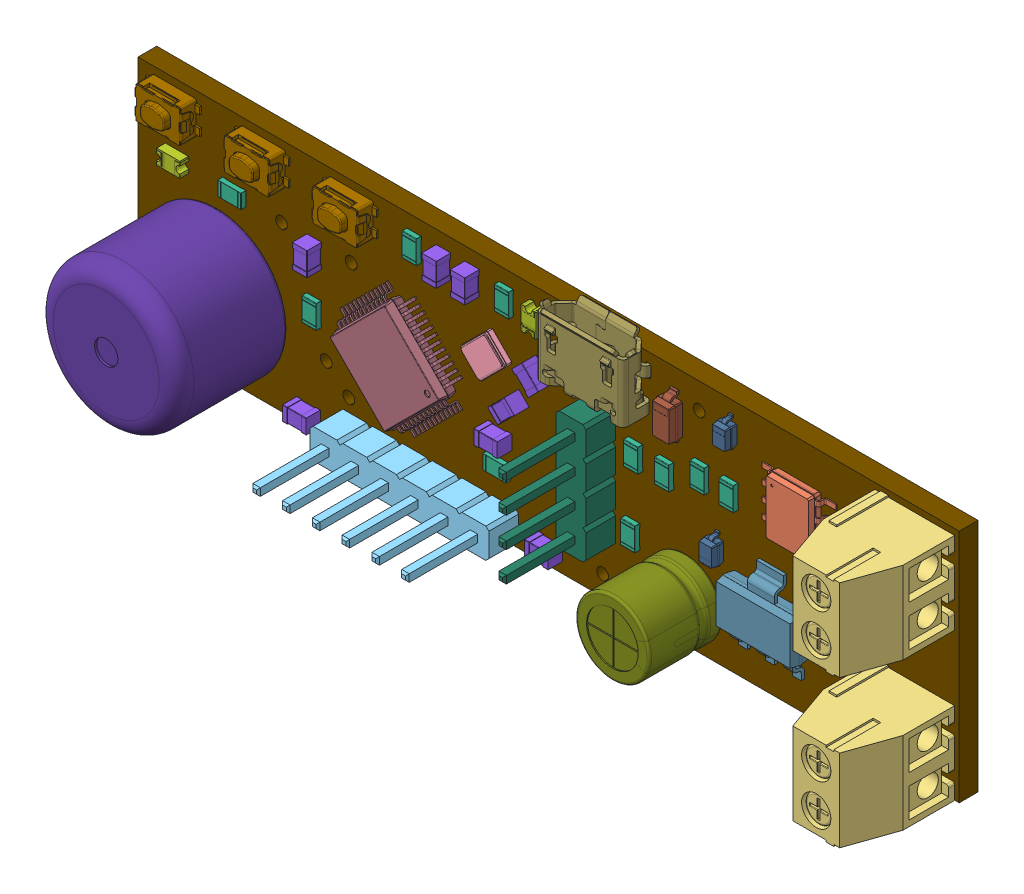
SolidWorks assembly SPD_DC_MotorHBridge, configuration Default. Lengths in mm.
Overall size (70.04 21.75 12.53).
84 component instances, 18 part files, 0 mates.
Components (placement in the parent):
- SPD_DC_MotorHBridge.step-1: SPD_DC_MotorHBridge.step [Default] at origin size (70.04 21.75 12.53)
  - R_1206_3216Metric.step-1: R_1206_3216Metric.step [Default] at (61.7855 -6.223 1.65) x (0 -1 0) z (0 0 1) size (3.2 1.6 0.55)
    - SOLID.step-1: SOLID.step [Default] at origin size (3.2 1.6 0.55)
  - HSOP-8-1EP_3.9x4.9mm_P1.27mm_EP2.41x3.1mm.step-1: HSOP-8-1EP_3.9x4.9mm_P1.27mm_EP2.41x3.1mm.step [Default] at (56.515 -5.2705 1.65) size (6.3 4.9 1.1)
    - SOLID-0.step-1: SOLID-0.step [Default] at origin size (6.3 4.9 1.1)
  - Screw_Terminal_Block_3.5mm_Blue_2-way.step-1: Screw_Terminal_Block_3.5mm_Blue_2-way.step [Default] at (66.294 -3.965 1.65) x (0 1 0) z (1 0 0) size (7.3 10.4 6.8)
    - COMPOUND.step-1: COMPOUND.step [Default] at origin size (7.3 10.4 6.8)
  - Crystal_SMD_SeikoEpson_TSX3225-4Pin_3.2x2.5mm_HandSoldering.step-1: Crystal_SMD_SeikoEpson_TSX3225-4Pin_3.2x2.5mm_HandSoldering.step [Default] at (29.972 -6.858 1.65) x (0.707107 0.707107 0) z (0 0 1) size (3.2 2.5 0.64)
    - SOLID-1.step-1: SOLID-1.step [Default] at origin size (3.2 2.5 0.64)
  - PinHeader_1x06_P2.54mm_Vertical.step-1: PinHeader_1x06_P2.54mm_Vertical.step [Default] at (31.242 -18.4912 1.65) x (0 -1 0) z (0 0 1) size (2.54 15.24 11.54)
    - SOLID-2.step-1: SOLID-2.step [Default] at origin size (2.54 15.24 11.54)
  - R_0805_2012Metric.step-1: R_0805_2012Metric.step [Default] at (31.496 -2.0828 1.65) x (0 1 0) z (0 0 1) size (2 1.2 0.45)
    - SOLID-3.step-1: SOLID-3.step [Default] at origin size (2 1.2 0.45)
  - D_0805_2012Metric.step-1: D_0805_2012Metric.step [Default] at (34.1376 -2.0828 1.65) x (0 1 0) z (0 0 1) size (2 1.27 0.8)
    - SOLID-4.step-1: SOLID-4.step [Default] at origin size (2 1.27 0.8)
  - R_0805_2012Metric.step-2: R_0805_2012Metric.step [Default] at (8.2804 -5.7912 1.65) x (-1 0 0) z (0 0 1) size (2 1.2 0.45)
    - SOLID-3.step-1: SOLID-3.step [Default] at origin size (2 1.2 0.45)
  - D_0805_2012Metric.step-2: D_0805_2012Metric.step [Default] at (3.4036 -5.7404 1.65) size (2 1.27 0.8)
    - SOLID-4.step-1: SOLID-4.step [Default] at origin size (2 1.27 0.8)
  - R_0805_2012Metric.step-3: R_0805_2012Metric.step [Default] at (23.622 -2.0828 1.65) x (0 -1 0) z (0 0 1) size (2 1.2 0.45)
    - SOLID-3.step-1: SOLID-3.step [Default] at origin size (2 1.2 0.45)
  - R_0805_2012Metric.step-4: R_0805_2012Metric.step [Default] at (42.5196 -8.0264 1.65) x (0 1 0) z (0 0 1) size (2 1.2 0.45)
    - SOLID-3.step-1: SOLID-3.step [Default] at origin size (2 1.2 0.45)
  - R_0805_2012Metric.step-5: R_0805_2012Metric.step [Default] at (45.1612 -8.0264 1.65) x (0 1 0) z (0 0 1) size (2 1.2 0.45)
    - SOLID-3.step-1: SOLID-3.step [Default] at origin size (2 1.2 0.45)
  - R_0805_2012Metric.step-6: R_0805_2012Metric.step [Default] at (42.2656 -13.97 1.65) x (0 1 0) z (0 0 1) size (2 1.2 0.45)
    - SOLID-3.step-1: SOLID-3.step [Default] at origin size (2 1.2 0.45)
  - R_0805_2012Metric.step-7: R_0805_2012Metric.step [Default] at (36.83 -13.97 1.65) x (0 1 0) z (0 0 1) size (2 1.2 0.45)
    - SOLID-3.step-1: SOLID-3.step [Default] at origin size (2 1.2 0.45)
  - R_0805_2012Metric.step-8: R_0805_2012Metric.step [Default] at (30.8864 -14.6812 1.65) size (2 1.2 0.45)
    - SOLID-3.step-1: SOLID-3.step [Default] at origin size (2 1.2 0.45)
  - R_0805_2012Metric.step-9: R_0805_2012Metric.step [Default] at (15.0876 -11.1252 1.65) x (0 -1 0) z (0 0 1) size (2 1.2 0.45)
    - SOLID-3.step-1: SOLID-3.step [Default] at origin size (2 1.2 0.45)
  - R_0805_2012Metric.step-10: R_0805_2012Metric.step [Default] at (50.6476 -6.8072 1.65) x (0 1 0) z (0 0 1) size (2 1.2 0.45)
    - SOLID-3.step-1: SOLID-3.step [Default] at origin size (2 1.2 0.45)
  - R_0805_2012Metric.step-11: R_0805_2012Metric.step [Default] at (48.1584 -6.7564 1.65) x (0 -1 0) z (0 0 1) size (2 1.2 0.45)
    - SOLID-3.step-1: SOLID-3.step [Default] at origin size (2 1.2 0.45)
  - C_0805_2012Metric.step-1: C_0805_2012Metric.step [Default] at (26.1112 -2.0828 1.65) x (0 -1 0) z (0 0 1) size (2 1.25 1.25)
    - SOLID-5.step-1: SOLID-5.step [Default] at origin size (2 1.25 1.25)
  - C_0805_2012Metric.step-2: C_0805_2012Metric.step [Default] at (28.5496 -2.0828 1.65) x (0 -1 0) z (0 0 1) size (2 1.25 1.25)
    - SOLID-5.step-1: SOLID-5.step [Default] at origin size (2 1.25 1.25)
  - C_0805_2012Metric.step-3: C_0805_2012Metric.step [Default] at (30.9372 -12.446 1.65) size (2 1.25 1.25)
    - SOLID-5.step-1: SOLID-5.step [Default] at origin size (2 1.25 1.25)
  - C_0805_2012Metric.step-4: C_0805_2012Metric.step [Default] at (15.0876 -6.8072 1.65) x (0 1 0) z (0 0 1) size (2 1.25 1.25)
    - SOLID-5.step-1: SOLID-5.step [Default] at origin size (2 1.25 1.25)
  - C_0805_2012Metric.step-5: C_0805_2012Metric.step [Default] at (59.2836 -12.7508 1.65) x (0 -1 0) z (0 0 1) size (2 1.25 1.25)
    - SOLID-5.step-1: SOLID-5.step [Default] at origin size (2 1.25 1.25)
  - C_0805_2012Metric.step-6: C_0805_2012Metric.step [Default] at (35.2552 -18.4912 1.65) size (2 1.25 1.25)
    - SOLID-5.step-1: SOLID-5.step [Default] at origin size (2 1.25 1.25)
  - C_0805_2012Metric.step-7: C_0805_2012Metric.step [Default] at (61.4172 -17.9324 1.65) x (0 1 0) z (0 0 1) size (2 1.25 1.25)
    - SOLID-5.step-1: SOLID-5.step [Default] at origin size (2 1.25 1.25)
  - C_0805_2012Metric.step-8: C_0805_2012Metric.step [Default] at (14.6304 -18.8468 1.65) x (-1 0 0) z (0 0 1) size (2 1.25 1.25)
    - SOLID-5.step-1: SOLID-5.step [Default] at origin size (2 1.25 1.25)
  - C_0805_2012Metric.step-9: C_0805_2012Metric.step [Default] at (34.29 -6.096 1.65) x (0.707107 -0.707107 0) z (0 0 1) size (2 1.25 1.25)
    - SOLID-5.step-1: SOLID-5.step [Default] at origin size (2 1.25 1.25)
  - C_0805_2012Metric.step-10: C_0805_2012Metric.step [Default] at (32.258 -9.398 1.65) x (0.707107 0.707107 0) z (0 0 1) size (2 1.25 1.25)
    - SOLID-5.step-1: SOLID-5.step [Default] at origin size (2 1.25 1.25)
  - KMR231NGLFS.step-1: KMR231NGLFS.step [Default] at (3.1496 -1.9685 1.65) x (-1 0 0) z (0 1 0) size (4.6 1.92 2.8)
    - SOLID-6.step-1: SOLID-6.step [Default] at origin size (4.6 1.92 2.8)
  - KMR231NGLFS.step-2: KMR231NGLFS.step [Default] at (10.7188 -1.9812 1.65) x (-1 0 0) z (0 1 0) size (4.6 1.92 2.8)
    - SOLID-6.step-1: SOLID-6.step [Default] at origin size (4.6 1.92 2.8)
  - KMR231NGLFS.step-3: KMR231NGLFS.step [Default] at (18.2372 -1.9812 1.65) x (-1 0 0) z (0 1 0) size (4.6 1.92 2.8)
    - SOLID-6.step-1: SOLID-6.step [Default] at origin size (4.6 1.92 2.8)
  - D_SOD-323.step-1: D_SOD-323.step [Default] at (49.53 -11.43 1.65) x (0 1 0) z (0 0 1) size (2.5 1.25 1.1)
    - SOLID-7.step-1: SOLID-7.step [Default] at origin size (2.5 1.25 1.1)
  - D_SOD-323.step-2: D_SOD-323.step [Default] at (50.673 -2.2225 1.65) x (0 -1 0) z (0 0 1) size (2.5 1.25 1.1)
    - SOLID-7.step-1: SOLID-7.step [Default] at origin size (2.5 1.25 1.1)
  - D_SOD-123.step-1: D_SOD-123.step [Default] at (45.8724 -3.4036 1.65) x (0 -1 0) z (0 0 1) size (3.8 1.6 1.25)
    - SOLID-8.step-1: SOLID-8.step [Default] at origin size (3.8 1.6 1.25)
  - USB_Micro-B_Amphenol_10118193-0001LF_Horizontal.step-1: USB_Micro-B_Amphenol_10118193-0001LF_Horizontal.step [Default] at (138.1935 -4.547 1.3) x (-1 0 0) z (0 1 0) size (7.87 3.61 5.71)
    - COMPOUND-9.step-1: COMPOUND-9.step [Default] at origin size (7.87 3.61 5.71)
  - LQFP-48_7x7mm_P0.5mm.step-1: LQFP-48_7x7mm_P0.5mm.step [Default] at (22.5552 -10.9855 1.65) x (-0.707107 -0.707107 0) z (0 0 1) size (9 9 1.5)
    - SOLID-10.step-1: SOLID-10.step [Default] at origin size (9 9 1.5)
  - Screw_Terminal_Block_3.5mm_Blue_2-way.step-2: Screw_Terminal_Block_3.5mm_Blue_2-way.step [Default] at (66.294 -16.538 1.65) x (0 1 0) z (1 0 0) size (7.3 10.4 6.8)
    - COMPOUND.step-1: COMPOUND.step [Default] at origin size (7.3 10.4 6.8)
  - SOT-223.step-1: SOT-223.step [Default] at (54.2036 -13.97 1.65) x (0 1 0) z (0 0 1) size (7 6.5 1.7)
    - SOLID-11.step-1: SOLID-11.step [Default] at origin size (7 6.5 1.7)
  - PinHeader_1x04_P2.54mm_Vertical.step-1: PinHeader_1x04_P2.54mm_Vertical.step [Default] at (39.5224 -14.478 1.65) x (-1 0 0) z (0 0 1) size (2.54 10.16 11.54)
    - SOLID-12.step-1: SOLID-12.step [Default] at origin size (2.54 10.16 11.54)
  - CP_Radial_D6.3mm_P2.50mm.step-1: CP_Radial_D6.3mm_P2.50mm.step [Default] at (45.5568 -16.3576 1.65) size (7.78 8.05 8.3)
    - SOLID-13.step-1: SOLID-13.step [Default] at origin size (7.78 8.05 8.3)
  - Buzzer_12x9.5RM7.6.step-1: Buzzer_12x9.5RM7.6.step [Default] at (10.668 -13.589 1.65) x (-1 0 0) z (0 0 1) size (12 12 12.53)
    - SOLID-14.step-1: SOLID-14.step [Default] at origin size (12 12 12.53)
  - COMPOUND-15.step-1: COMPOUND-15.step [Default] at origin size (70.04 20.07 1.6)
